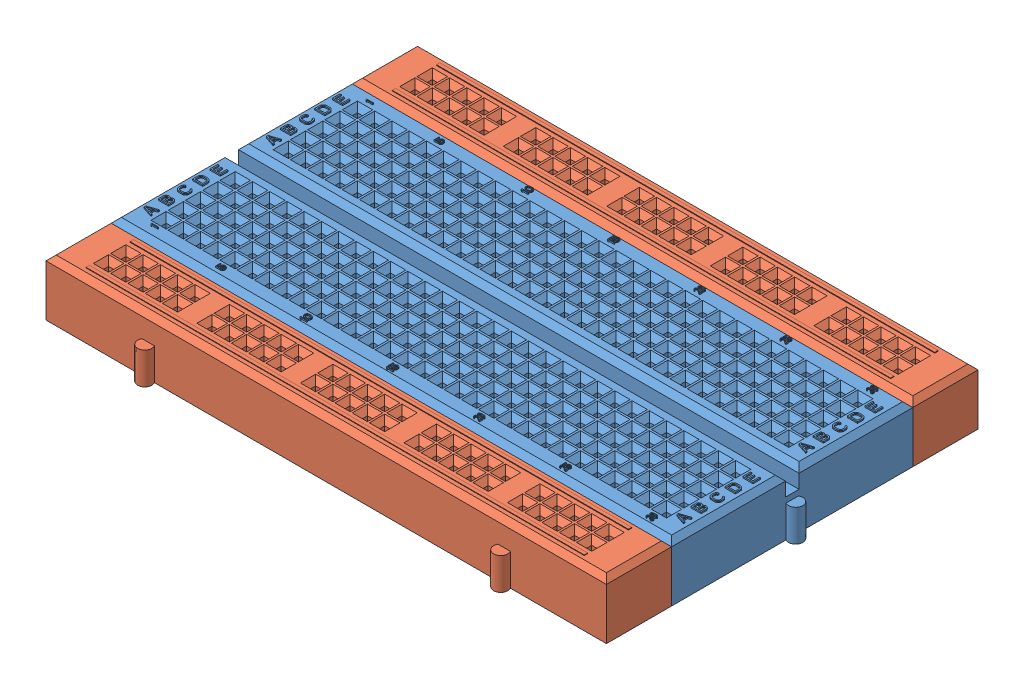
SolidWorks assembly breadboard_350_pos_asm, configuration Default. Lengths in mm.
Overall size (84.06 8.5 56.26).
3 component instances, 2 part files, 0 mates.
Components (placement in the parent):
- BREADBOARD_350_POS_CENTER-1: BREADBOARD_350_POS_CENTER [Default] at origin size (84.06 8.5 37.06)
- BREADBOARD_350_POS_SIDE-1: BREADBOARD_350_POS_SIDE [Default] at (0 0 22.55) size (82.5 8.4 11.16)
- BREADBOARD_350_POS_SIDE-2: BREADBOARD_350_POS_SIDE [Default] at (0 0 -22.55) size (82.5 8.4 11.16)
